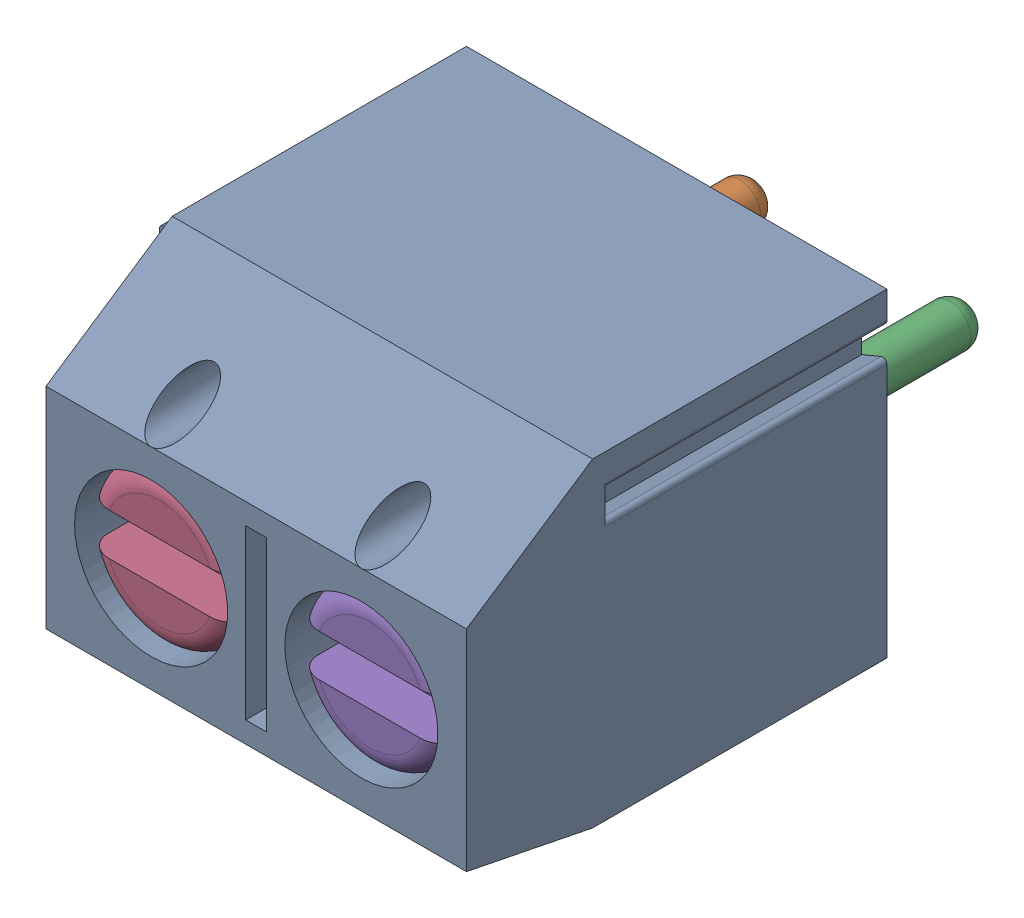
SolidWorks assembly DG301-5.0-02 (OPTION 1)-1, configuration Default. Lengths in mm.
Overall size (10.6 7.6 14.4).
7 component instances, 4 part files, 0 mates.
Components (placement in the parent):
- DG301-5.0-02-body-1: DG301-5.0-02-body [Default] at origin size (10.6 7.6 10)
- DG301-5.0-pin-1: DG301-5.0-pin [Default] at (0 0.5 2.85) size (3.9 4 9.9)
- DG301-5.0-pin-2: DG301-5.0-pin [Default] at (5 0.5 2.85) size (3.9 4 9.9)
- DG301-5.0-screw-1: DG301-5.0-screw [Default] at (0 0 4) size (3.6 3.6 5.84)
- DG301-5.0-screw-2: DG301-5.0-screw [Default] at (5 0 4) size (3.6 3.6 5.84)
- DG301-5.0-wire_prot-1: DG301-5.0-wire_prot [Default] at (0 0 5.5) size (3.9 5.45 2.85)
- DG301-5.0-wire_prot-2: DG301-5.0-wire_prot [Default] at (5 0 5.5) size (3.9 5.45 2.85)
